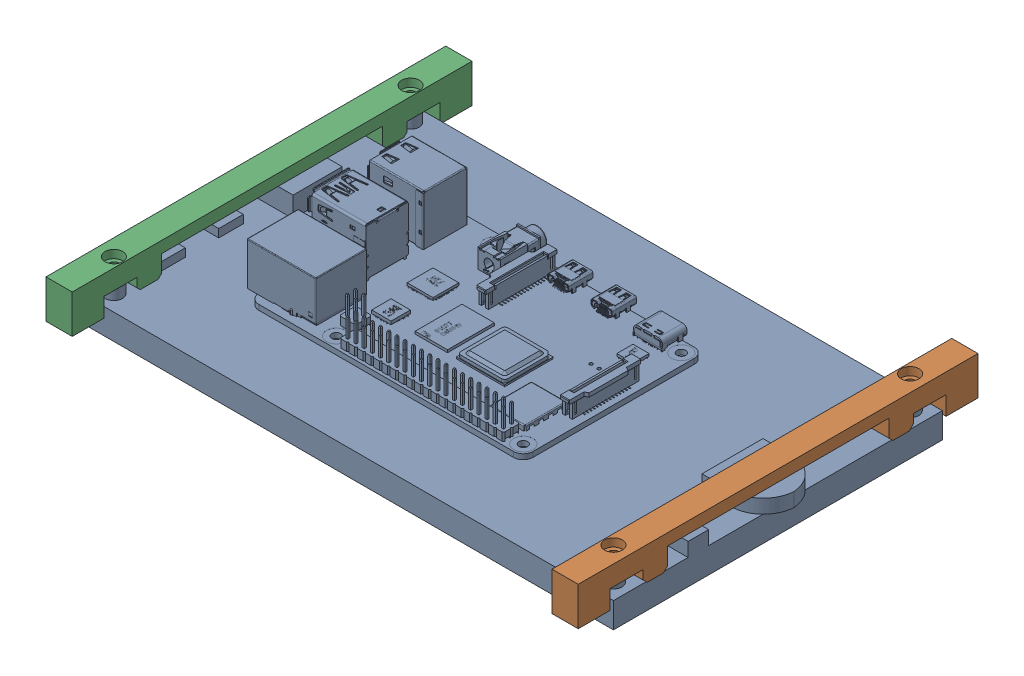
SolidWorks assembly lcd_bracket, configuration Default. Lengths in mm.
Overall size (224.85 117.64 187).
4 component instances, 3 part files, 10 mates.
Components (placement in the parent):
- ELCROW_7_INCH-1: ELCROW_7_INCH [Default] at (96.8733 96.9597 97.0199) size (167.92 14.22 102)
- LCD_bracket-1: LCD_bracket [Default] at (175.3343 96.4517 97.0099) size (8.13 11.94 123.95)
- LCD_bracket-2: LCD_bracket [Default] at (18.4123 96.4517 97.0099) x (-1 0 0) z (0 0 -1) size (8.13 11.94 123.95)
- Raspberry Pi 4 Model B-1: Raspberry Pi 4 Model B [Default] at (93.6433 113.3682 104.7799) x (-1 0 0) z (0 0 -1) size (88.99 19.9 58.4)
Mates (geometry in assembly coordinates):
- Concentric1: concentric anti-aligned: circle of ELCROW_7_INCH-1; circle of LCD_bracket-1
- Parallel1: parallel aligned: plane of ELCROW_7_INCH-1 through (179.3233 104.8337 46.0199) normal (1 0 0); plane of LCD_bracket-1 through (179.3983 114.7397 33.5099) normal (1 0 0)
- Coincident2: coincident anti-aligned: plane of ELCROW_7_INCH-1 through (174.3183 108.6437 51.0199) normal (0 1 0); plane of LCD_bracket-1 through (175.3343 108.6437 97.0099) normal (0 -1 0)
- Concentric2: concentric aligned: circle of ELCROW_7_INCH-1; circle of LCD_bracket-2
- Parallel2: parallel aligned: plane of ELCROW_7_INCH-1 through (14.4233 104.8337 46.0199) normal (-1 0 0); plane of LCD_bracket-2 through (14.3483 114.7397 160.5099) normal (-1 0 0)
- Coincident4: coincident anti-aligned: plane of ELCROW_7_INCH-1 through (19.4283 108.6437 143.0199) normal (0 1 0); plane of LCD_bracket-2 through (18.4123 108.6437 97.0099) normal (0 -1 0)
- Distance1: distance = 9.3345 mm aligned: plane of ELCROW_7_INCH-1 through (96.8733 104.8337 97.0199) normal (0 1 0); plane of Raspberry Pi 4 Model B-1 through (93.6433 114.1682 104.7799) normal (0 1 0)
- Parallel3: parallel aligned: plane of ELCROW_7_INCH-1 through (14.4233 104.8337 148.0199) normal (0 0 1); plane of Raspberry Pi 4 Model B-1 through (136.1433 114.1682 132.7799) normal (0 0 1)
- Distance2: distance = 15.24 mm aligned: plane of Raspberry Pi 4 Model B-1 through (136.1433 114.1682 132.7799) normal (0 0 1); plane of ELCROW_7_INCH-1 through (14.4233 104.8337 148.0199) normal (0 0 1)
- Distance3: distance = 43.18 mm aligned: plane of Raspberry Pi 4 Model B-1 through (136.1433 114.1682 132.7799) normal (1 0 0); plane of ELCROW_7_INCH-1 through (179.3233 104.8337 46.0199) normal (1 0 0)
